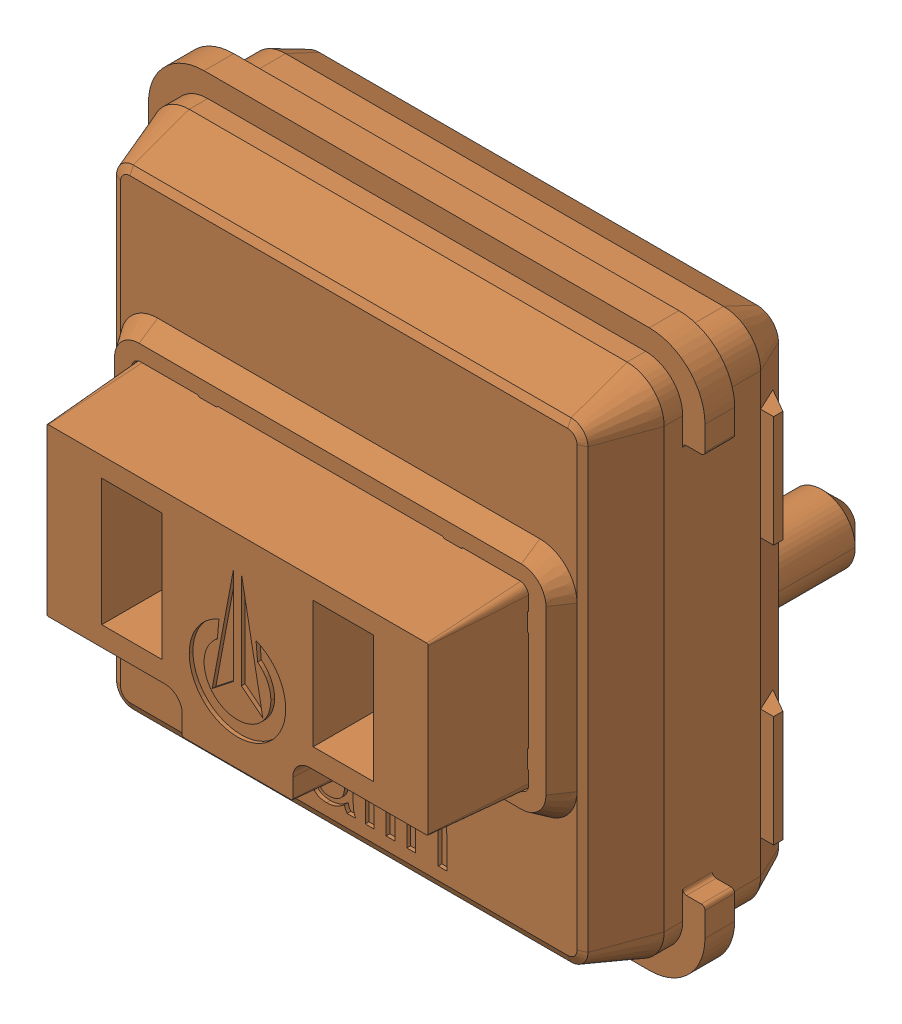
SolidWorks assembly SW3_1.step, configuration Default. Lengths in mm.
Overall size (15 15 11.1).
2 component instances, 2 part files, 0 mates.
Components (placement in the parent):
- WS2812-2020_1.step-11: WS2812-2020_1.step [Default] at (538.4468 231.0345 0.3) x (1 0 0) z (0 -1 0) size (2.2 0.86 2)
- Kailh LP Choc Burnt Orange_1.step-11: Kailh LP Choc Burnt Orange_1.step [Default] at (538.3402 226.3933 2.7) x (0 -1 0) z (-1 0 0) size (15 11.1 15)
